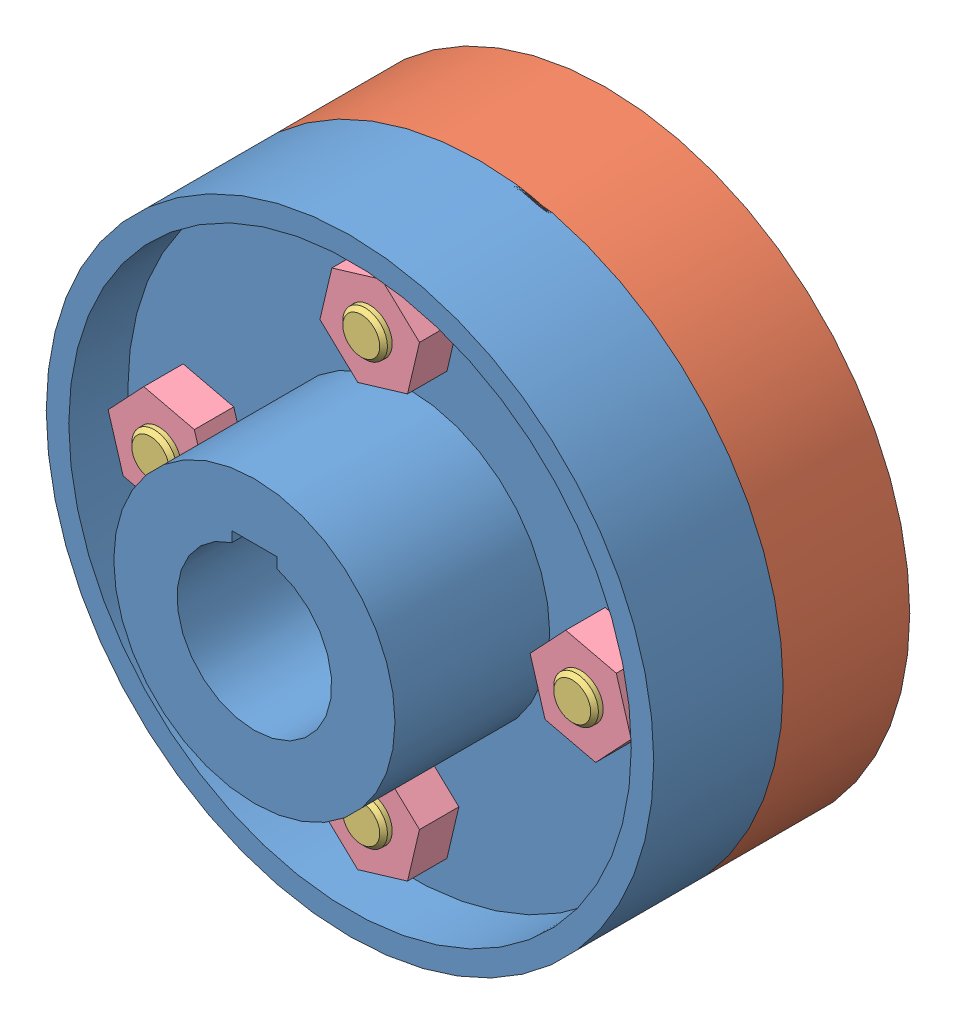
SolidWorks assembly flange coupling, configuration Default. Lengths in mm.
Overall size (216 216 159.14).
12 component instances, 6 part files, 13 mates.
Components (placement in the parent):
- Part4-1: Part4 [Default] at (70.5932 99.1266 142.8288) size (216 216 85)
- Part5-1: Part5 [Default] at (70.5932 99.1266 143.8288) x (-1 0 0) z (0 0 -1) size (216 216 80)
- Part6^flange coupling-1: Part6^flange coupling [Default] at origin (virtual)
- Part2-1: Part2 [Default] at (137.2262 82.6546 118.8288) x (-0.923728 -0.383049 0) z (0 0 -1) size (34.84 36.33 78)
- Part3-1: Part3 [Default] at (145.5932 99.1266 167.8288) x (-0.685361 -0.728203 0) z (0 0 1) size (36.95 32 14)
- Part2-6: Part2 [Default] at (87.0652 165.7595 118.8288) x (0.383049 -0.923728 0) z (0 0 -1) size (34.84 36.33 78)
- Part2-7: Part2 [Default] at (3.9603 115.5986 118.8288) x (0.923728 0.383049 0) z (0 0 -1) size (34.84 36.33 78)
- Part2-8: Part2 [Default] at (54.1213 32.4936 118.8288) x (-0.383049 0.923728 0) z (0 0 -1) size (34.84 36.33 78)
- Part3-5: Part3 [Default] at (70.5932 174.1266 167.8288) x (0.728203 -0.685361 0) z (0 0 1) size (36.95 32 14)
- Part3-6: Part3 [Default] at (-4.4068 99.1266 167.8288) x (0.685361 0.728203 0) z (0 0 1) size (36.95 32 14)
- Part3-7: Part3 [Default] at (70.5932 24.1266 167.8288) x (-0.728203 0.685361 0) z (0 0 1) size (36.95 32 14)
- Part1-3: Part1 [Default] at (78.5932 119.8779 108.6809) x (0 -0.016664 0.999861) z (-1 0 0) size (90 10 16)
Mates (geometry in assembly coordinates):
- Concentric1: concentric anti-aligned: cylinder of Part4-1 through (70.5932 99.1266 222.8288) axis (0 0 -1) radius 27.5; cylinder of Part5-1 through (70.5932 99.1266 63.8288) axis (0 0 1) radius 27.5
- Coincident3: coincident aligned: plane of Part4-1 through (62.5932 129.1266 137.8288) normal (0 -1 0); plane of Part5-1 through (78.5932 129.1266 143.8288) normal (0 -1 0)
- Coincident4: coincident anti-aligned: plane of Part4-1 through (70.5932 99.1266 137.8288) normal (0 0 -1); plane of Part5-1 through (70.5932 99.1266 137.8288) normal (0 0 1)
- Lock1: lock: unknown of Part4-1; unknown of Part5-1
- Concentric3: concentric aligned: cylinder of Part5-1 through (145.5932 99.1266 143.8288) axis (0 0 -1) radius 8; cylinder of Part2-1 through (145.5932 99.1266 184.8288) axis (0 0 -1) radius 7.9375
- Coincident7: coincident anti-aligned: plane of Part5-1 through (70.5932 99.1266 118.8288) normal (0 0 -1); plane of Part2-1 through (137.2262 82.6546 118.8288) normal (0 0 1)
- Lock2: lock: unknown of Part4-1; unknown of Part2-1
- Coincident10: coincident aligned: line of Part2-1 through (145.5932 99.1266 183.4546) axis (0 0 -1); line of Part3-1 through (145.5932 99.1266 181.8288) axis (0 0 -1)
- Coincident11: coincident anti-aligned: plane of Part4-1 through (70.5932 99.1266 167.8288) normal (0 0 1); plane of Part3-1 through (145.5932 99.1266 167.8288) normal (0 0 -1)
- Lock3: lock: unknown of Part2-1; unknown of Part3-1
- Coincident15: coincident anti-aligned: plane of Part4-1 through (62.5932 129.1266 137.8288) normal (0 -1 0); plane of Part1-3 through (62.5932 129.1266 63.8288) normal (0 1 0)
- Coincident16: coincident anti-aligned: plane of Part4-1 through (62.5932 129.1266 137.8288) normal (1 0 0); plane of Part1-3 through (62.5932 119.8779 108.6809) normal (-1 0 0)
- Coincident26: coincident: point of Part5-1; unknown of Part1-3
